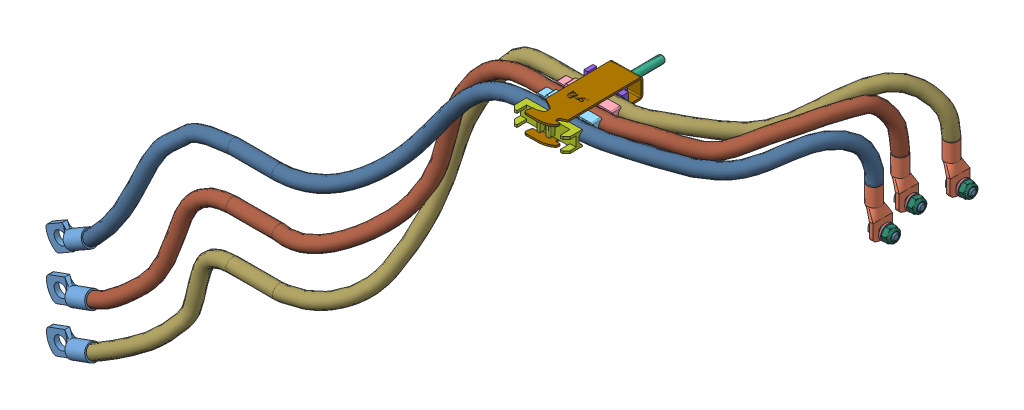
SolidWorks assembly PUTM-H-TS-EB-ENGINE_POWER_CABLE-Assembly, configuration Domyślna. Lengths in mm.
Overall size (497.87 307.2 278.87).
27 component instances, 15 part files, 21 mates.
Components (placement in the parent):
- PUTM-H-TS-Cable-Lug-PK-35-10-2: PUTM-H-TS-Cable-Lug-PK-35-10 [Domyślna] at (1258.1206 -141.684 481.9566) x (0.939693 0.34202 0) z (0.34202 -0.939693 0) size (44 15.07 18.5)
- PUTM-H-TS-Cable-Lug-PK-35-10-3: PUTM-H-TS-Cable-Lug-PK-35-10 [Domyślna] at (1258.1206 -104.684 481.9566) x (0.939693 0.34202 0) z (0.34202 -0.939693 0) size (44 15.07 18.5)
- PUTM-H-TS-Cable-Lug-PK-35-10-4: PUTM-H-TS-Cable-Lug-PK-35-10 [Domyślna] at (1258.2679 -68 481.9566) x (0.866025 0.5 0) z (0.5 -0.866025 0) size (44 15.07 18.5)
- PUTM-H-TS-Cable-Lug-PK-25-6-1: PUTM-H-TS-Cable-Lug-PK-25-6 [Domyślna] at (1732.7166 77.5 289.4485) x (0 1 0) z (0.000011 0 1) size (37 12.55 16)
- PUTM-H-TS-Cable-Lug-PK-25-6-2: PUTM-H-TS-Cable-Lug-PK-25-6 [Domyślna] at (1722.4986 77.5 258.0021) x (0 1 0) z (0.000011 0 1) size (37 12.55 16)
- PUTM-H-TS-Cable-Lug-PK-25-6-3: PUTM-H-TS-Cable-Lug-PK-25-6 [Domyślna] at (1732.7159 77.5 226.5555) x (0 1 0) z (0.000011 0 1) size (37 12.55 16)
- PUTM-H-EB-Cable_Clams-Assembly-1: PUTM-H-EB-Cable_Clams-Assembly [Domyślna] at (1586.8702 140.3587 422.7526) x (0.000007 0.999999 0.001411) z (-0.009596 0.001411 -0.999953) size (18 45 101.5)
  - CFXL12_3_2.stp-1: CFXL12_3_2.stp [Domyślna] at origin size (18 45 101.5)
    - CFXL12.3.stp-1: CFXL12.3.stp [Domyślna] at origin size (10 24 3.5)
    - CFXL12.3-0.stp-1: CFXL12.3-0.stp [Domyślna] at origin size (16 45 8)
    - CFXL12.3-1.stp-1: CFXL12.3-1.stp [Domyślna] at origin size (16 45 8)
    - CFXL12.3-2.stp-1: CFXL12.3-2.stp [Domyślna] at origin size (6 6 42.8)
    - CFXL12.3-3.stp-1: CFXL12.3-3.stp [Domyślna] at origin size (12 45 13)
    - CFXL12.3-4.stp-1: CFXL12.3-4.stp [Domyślna] at origin size (18 31 7.5)
    - CFXL12.3-5.stp-1: CFXL12.3-5.stp [Domyślna] at origin size (16 24 73.5)
- PUTM-H-TS-EB-ENGINE_POWER_CABLE-Cable_U1-1: PUTM-H-TS-EB-ENGINE_POWER_CABLE-Cable_U1 [Domyślna] at (1725.7166 118.7045 286.8463) x (0 -1 0) z (0 0 1) size (203.87 446.64 213.69)
- PUTM-H-TS-EB-ENGINE_POWER_CABLE-Cable_V2-1: PUTM-H-TS-EB-ENGINE_POWER_CABLE-Cable_V2 [Domyślna] at (1715.4986 108.1136 254.3772) size (431.94 252.61 244.09)
- PUTM-H-TS-EB-ENGINE_POWER_CABLE-Cable_W3-1: PUTM-H-TS-EB-ENGINE_POWER_CABLE-Cable_W3 [Domyślna] at (1725.7159 110.1091 222.5646) size (442.83 287.29 275.3)
- PUTM-FT-FABORY_ISO7089-1: PUTM-FT-FABORY_ISO7089 [M6 [38093.060.001]] at (1735.3159 77 226.5554) x (-0.000004 -0.924211 -0.381882) z (1 0 -0.000011) size (12 12 1.6)
- PUTM-FT-FABORY_DIN933-3: PUTM-FT-FABORY_DIN933 [M6x14 [01210.060.014]] at (1725.7159 77 226.5556) x (-1 0 0.000011) z (-0.000004 -0.924211 -0.381882) size (18 11.55 10)
- PUTM-FT-FABORY_DIN985-1: PUTM-FT-FABORY_DIN985 [M6 [12348.060.001]] at (1736.9159 77 226.5554) x (-0.000004 -0.924211 -0.381882) z (1 0 -0.000011) size (11.9 10.35 6.18)
- PUTM-FT-FABORY_DIN933-4: PUTM-FT-FABORY_DIN933 [M6x14 [01210.060.014]] at (1715.4986 77 258.0022) x (-1 0 0.000011) z (-0.000004 -0.924211 -0.381882) size (18 11.55 10)
- PUTM-FT-FABORY_DIN933-5: PUTM-FT-FABORY_DIN933 [M6x14 [01210.060.014]] at (1725.7166 77 289.4486) x (-1 0 0.000011) z (-0.000004 -0.924211 -0.381882) size (18 11.55 10)
- PUTM-FT-FABORY_ISO7089-2: PUTM-FT-FABORY_ISO7089 [M6 [38093.060.001]] at (1735.3166 77 289.4485) x (-0.000004 -0.924211 -0.381882) z (1 0 -0.000011) size (12 12 1.6)
- PUTM-FT-FABORY_ISO7089-3: PUTM-FT-FABORY_ISO7089 [M6 [38093.060.001]] at (1725.0986 77 258.0021) x (-0.000004 -0.924211 -0.381882) z (1 0 -0.000011) size (12 12 1.6)
- PUTM-FT-FABORY_DIN985-2: PUTM-FT-FABORY_DIN985 [M6 [12348.060.001]] at (1726.6986 77 258.0021) x (-0.000004 -0.924211 -0.381882) z (1 0 -0.000011) size (11.9 10.35 6.18)
- PUTM-FT-FABORY_DIN985-3: PUTM-FT-FABORY_DIN985 [M6 [12348.060.001]] at (1736.9166 77 289.4485) x (-0.000004 -0.924211 -0.381882) z (1 0 -0.000011) size (11.9 10.35 6.18)
Mates (geometry in assembly coordinates):
- Wspólnie10: coincident anti-aligned: plane of PUTM-H-TS-Cable-Lug-PK-25-6-1 through (1725.7166 107 289.4486) normal (0 1 0); plane of PUTM-H-TS-EB-ENGINE_POWER_CABLE-Cable_U1-1 through (1725.7166 107 289.4486) normal (0 -1 0)
- Koncentryczne9: concentric anti-aligned: cylinder of PUTM-H-TS-Cable-Lug-PK-25-6-1 through (1725.7166 107 289.4486) axis (0 -1 0) radius 5.5; cylinder of PUTM-H-TS-EB-ENGINE_POWER_CABLE-Cable_U1-1 through (1725.7166 107 289.4486) axis (0 1 0) radius 5.5
- Wspólnie11: coincident anti-aligned: plane of PUTM-H-TS-Cable-Lug-PK-25-6-2 through (1715.4986 107 258.0022) normal (0 1 0); plane of PUTM-H-TS-EB-ENGINE_POWER_CABLE-Cable_V2-1 through (1715.4986 107 258.0022) normal (0 -1 0)
- Koncentryczne10: concentric anti-aligned: cylinder of PUTM-H-TS-Cable-Lug-PK-25-6-2 through (1715.4986 107 258.0022) axis (0 -1 0) radius 5.5; cylinder of PUTM-H-TS-EB-ENGINE_POWER_CABLE-Cable_V2-1 through (1715.4986 107 258.0022) axis (0 1 0) radius 5.5
- Wspólnie12: coincident anti-aligned: plane of PUTM-H-TS-Cable-Lug-PK-25-6-3 through (1725.7159 107 226.5556) normal (0 1 0); plane of PUTM-H-TS-EB-ENGINE_POWER_CABLE-Cable_W3-1 through (1725.7159 107 226.5556) normal (0 -1 0)
- Koncentryczne11: concentric anti-aligned: cylinder of PUTM-H-TS-Cable-Lug-PK-25-6-3 through (1725.7159 107 226.5556) axis (0 -1 0) radius 5.5; cylinder of PUTM-H-TS-EB-ENGINE_POWER_CABLE-Cable_W3-1 through (1725.7159 107 226.5556) axis (0 1 0) radius 5.5
- Wspólnie16: coincident anti-aligned: plane of PUTM-H-TS-Cable-Lug-PK-25-6-3 through (1729.7159 77.5 226.5555) normal (-1 0 0.000011); plane of PUTM-FT-FABORY_DIN933-3 through (1729.7158 78.9094 221.9345) normal (1 0 -0.000011)
- Koncentryczne16: concentric aligned: cylinder of PUTM-H-TS-Cable-Lug-PK-25-6-3 through (1729.7159 77 226.5555) axis (1 0 -0.000011) radius 3.25; cylinder of PUTM-FT-FABORY_DIN933-3 through (1743.7159 77 226.5554) axis (1 0 -0.000011) radius 3
- Koncentryczne17: concentric anti-aligned: cylinder of PUTM-FT-FABORY_ISO7089-1 through (1736.9159 77 226.5554) axis (-1 0 0.000011) radius 3.2; cylinder of PUTM-FT-FABORY_DIN933-3 through (1743.7159 77 226.5554) axis (1 0 -0.000011) radius 3
- Wspólnie17: coincident anti-aligned: plane of PUTM-FT-FABORY_ISO7089-1 through (1736.9159 77 226.5554) normal (1 0 -0.000011); plane of PUTM-FT-FABORY_DIN985-1 through (1736.9159 77 226.5554) normal (-1 0 0.000011)
- Koncentryczne18: concentric anti-aligned: cylinder of PUTM-FT-FABORY_DIN933-3 through (1743.7159 77 226.5554) axis (1 0 -0.000011) radius 3; cylinder of PUTM-FT-FABORY_DIN985-1 through (1740.9159 77 226.5554) axis (-1 0 0.000011) radius 3
- Wspólnie18: coincident anti-aligned: plane of PUTM-H-TS-Cable-Lug-PK-25-6-2 through (1719.4986 77.5 258.0021) normal (-1 0 0.000011); plane of PUTM-FT-FABORY_DIN933-4 through (1719.4986 78.9094 253.3811) normal (1 0 -0.000011)
- Koncentryczne19: concentric aligned: cylinder of PUTM-H-TS-Cable-Lug-PK-25-6-2 through (1719.4986 77 258.0021) axis (1 0 -0.000011) radius 3.25; cylinder of PUTM-FT-FABORY_DIN933-4 through (1733.4986 77 258.002) axis (1 0 -0.000011) radius 3
- Wspólnie19: coincident anti-aligned: plane of PUTM-H-TS-Cable-Lug-PK-25-6-1 through (1729.7166 77.5 289.4485) normal (-1 0 0.000011); plane of PUTM-FT-FABORY_DIN933-5 through (1729.7165 78.9094 284.8275) normal (1 0 -0.000011)
- Koncentryczne20: concentric aligned: cylinder of PUTM-H-TS-Cable-Lug-PK-25-6-1 through (1729.7166 77 289.4485) axis (1 0 -0.000011) radius 3.25; cylinder of PUTM-FT-FABORY_DIN933-5 through (1743.7166 77 289.4484) axis (1 0 -0.000011) radius 3
- Koncentryczne25: concentric anti-aligned: cylinder of PUTM-FT-FABORY_DIN933-4 through (1733.4986 77 258.002) axis (1 0 -0.000011) radius 3; cylinder of PUTM-FT-FABORY_ISO7089-3 through (1726.6986 77 258.0021) axis (-1 0 0.000011) radius 3.2
- Wspólnie27: coincident anti-aligned: plane of PUTM-FT-FABORY_ISO7089-3 through (1726.6986 77 258.0021) normal (1 0 -0.000011); plane of PUTM-FT-FABORY_DIN985-2 through (1726.6986 77 258.0021) normal (-1 0 0.000011)
- Koncentryczne26: concentric anti-aligned: cylinder of PUTM-FT-FABORY_DIN933-4 through (1733.4986 77 258.002) axis (1 0 -0.000011) radius 3; cylinder of PUTM-FT-FABORY_DIN985-2 through (1730.6986 77 258.002) axis (-1 0 0.000011) radius 3
- Koncentryczne27: concentric anti-aligned: cylinder of PUTM-FT-FABORY_DIN933-5 through (1743.7166 77 289.4484) axis (1 0 -0.000011) radius 3; cylinder of PUTM-FT-FABORY_ISO7089-2 through (1736.9166 77 289.4485) axis (-1 0 0.000011) radius 3.2
- Wspólnie29: coincident anti-aligned: plane of PUTM-FT-FABORY_ISO7089-2 through (1736.9166 77 289.4485) normal (1 0 -0.000011); plane of PUTM-FT-FABORY_DIN985-3 through (1736.9166 77 289.4485) normal (-1 0 0.000011)
- Koncentryczne28: concentric anti-aligned: cylinder of PUTM-FT-FABORY_DIN933-5 through (1743.7166 77 289.4484) axis (1 0 -0.000011) radius 3; cylinder of PUTM-FT-FABORY_DIN985-3 through (1740.9166 77 289.4484) axis (-1 0 0.000011) radius 3
